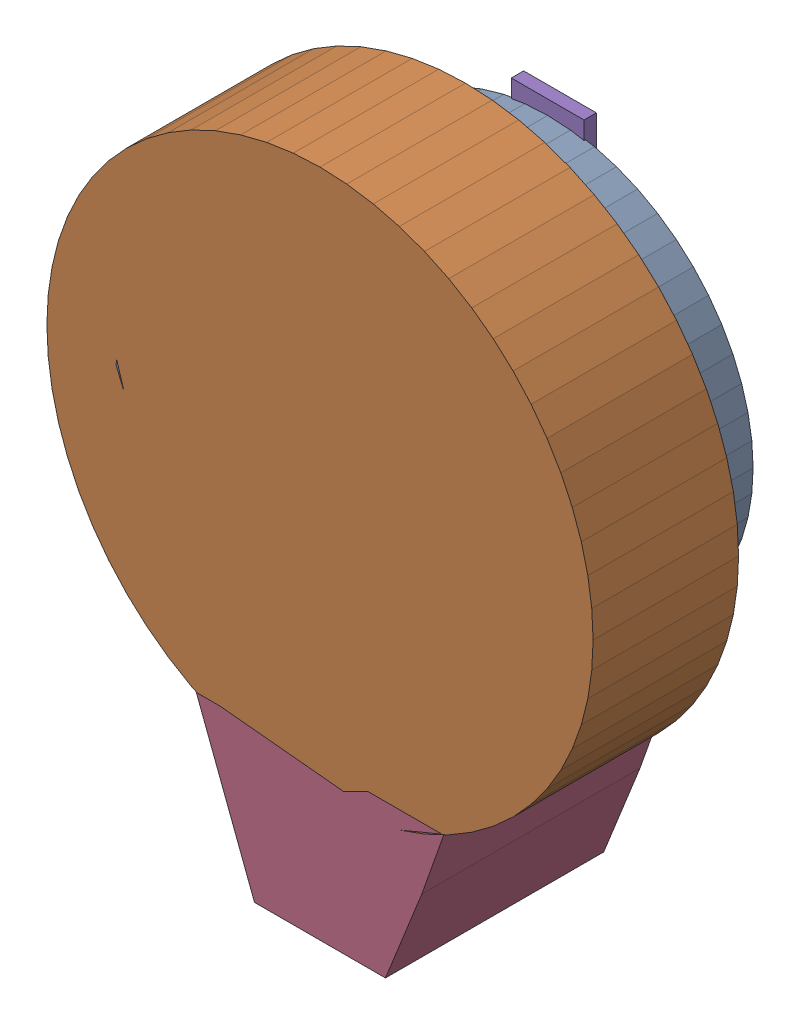
SolidWorks assembly BATT1, configuration Default. Lengths in mm.
Overall size (19.07 23.38 8.38).
10 component instances, 5 part files, 0 mates.
Components (placement in the parent):
- 402662032-1: 402662032 [Default] at (116.205 65.0494 -9.1034) size (14.25 14.25 8)
  - Extruded_2-1: Extruded_2 [Default] at origin size (14.25 14.25 8)
- 402661904-1: 402661904 [Default] at (116.205 65.0494 -6.1824) size (19.07 19.07 5.08)
  - Extruded_3-1: Extruded_3 [Default] at origin size (19.07 19.07 5.08)
- 402659984-1: 402659984 [Default] at (116.205 54.1274 -9.4844) size (2.54 3.56 8.38)
  - Extruded_4-1: Extruded_4 [Default] at origin size (2.54 3.56 8.38)
- 402659600-1: 402659600 [Default] at (116.205 53.8734 -8.7224) size (8.64 5.33 7.62)
  - Extruded_5-1: Extruded_5 [Default] at origin size (8.64 5.33 7.62)
- 402659344-1: 402659344 [Default] at (116.205 62.5094 -9.4844) size (2.54 20.32 0.43)
  - Extruded_6-1: Extruded_6 [Default] at origin size (2.54 20.32 0.43)
